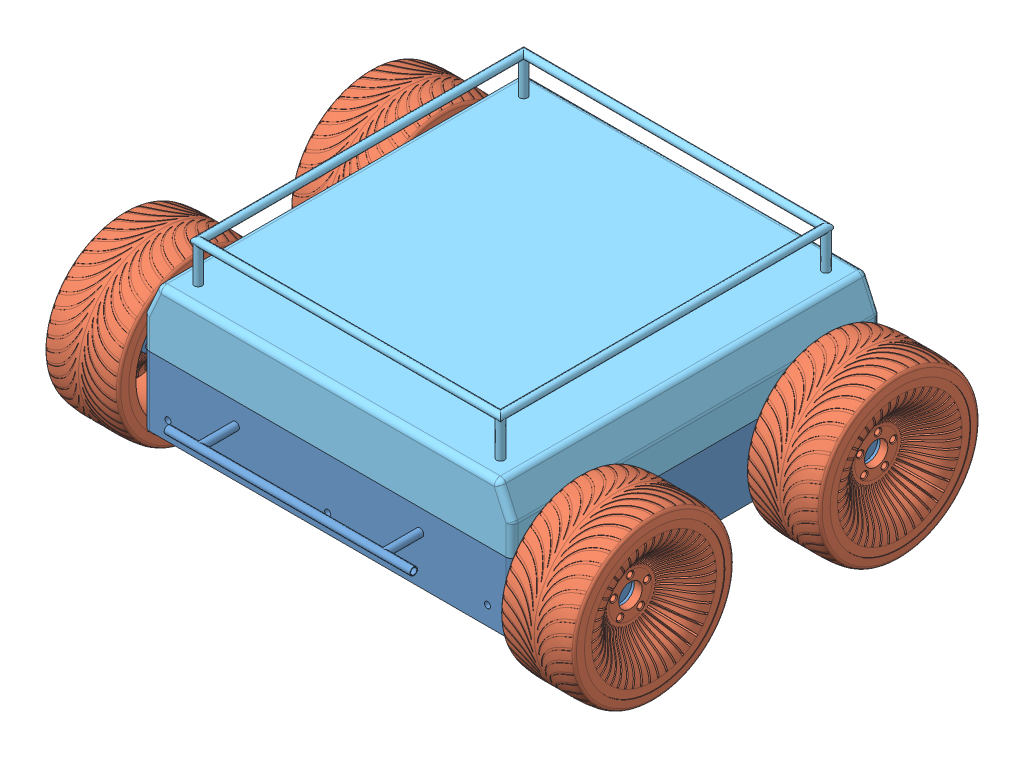
SolidWorks assembly FINAL UGV, configuration Default. Lengths in mm.
Overall size (1744.11 737.37 1465).
11 component instances, 5 part files, 28 mates.
Components (placement in the parent):
- BASE - Copy-2: BASE - Copy [Default<As Machined>] at (827.8363 661.6568 1059.2236) size (1520 225 1465)
- 18 x 9.5 wheel-3: 18 x 9.5 wheel [Default] at (1587.8363 756.6568 659.2236) x (1 0 0) z (0 0.112104 0.993697) size (252.9 542.37 542.37)
- 18 x 9.5 wheel-4: 18 x 9.5 wheel [Default] at (1587.8363 756.6568 1459.2236) size (252.9 542.37 542.37)
- 18 x 9.5 wheel-5: 18 x 9.5 wheel [Default] at (67.8363 756.6568 659.2236) x (-1 0 0) z (0 0 -1) size (252.9 542.37 542.37)
- 18 x 9.5 wheel-6: 18 x 9.5 wheel [Default] at (67.8363 756.6568 1459.2236) x (-1 0 0) z (0 0 -1) size (252.9 542.37 542.37)
- chassis-1: chassis [Default<As Machined>] at (1295.9851 766.5317 2607.767) size (1075 344.87 1105)
- Motenergy ME1114-1: Motenergy ME1114 [Default] at (405.8363 756.6568 659.2236) x (0 -1 -0.000674) z (-1 0 0) size (200 240 212.88)
- Motenergy ME1114-2: Motenergy ME1114 [Default] at (1229.8363 756.6568 1459.8036) x (0 -1 0) z (1 0 0) size (200 240 212.88)
- Motenergy ME1114-3: Motenergy ME1114 [Default] at (1229.8363 756.6568 658.6436) x (0 1 0) z (1 0 0) size (200 240 212.88)
- Motenergy ME1114-4: Motenergy ME1114 [Default] at (405.8363 756.6568 1459.8036) x (0 -1 0) z (-1 0 0) size (200 240 212.88)
- top-2: top [Default<As Machined>] at (827.8363 789.6568 459.2236) size (1200 332.5 1200)
Mates (geometry in assembly coordinates):
- Concentric3: concentric: circle of BASE - Copy-2; circle of 18 x 9.5 wheel-3
- Coincident5: coincident: plane of BASE - Copy-2 through (1587.8363 756.6568 659.2236) normal (1 0 0); plane of 18 x 9.5 wheel-3 through (1587.8363 832.8295 650.6302) normal (-1 0 0)
- Parallel3: parallel: cylinder of BASE - Copy-2 through (1577.8363 774.3187 713.5813) axis (1 0 0) radius 9.525; cylinder of 18 x 9.5 wheel-3 through (1448.9259 813.4466 652.8169) axis (1 0 0) radius 9.525
- Concentric5: concentric: circle of BASE - Copy-2; circle of 18 x 9.5 wheel-4
- Coincident6: coincident: plane of BASE - Copy-2 through (1587.8363 756.6568 1459.2236) normal (1 0 0); plane of 18 x 9.5 wheel-4 through (1587.8363 833.3127 1459.2236) normal (-1 0 0)
- Concentric6: concentric: circle of BASE - Copy-2; circle of 18 x 9.5 wheel-5
- Coincident7: coincident: plane of BASE - Copy-2 through (67.8363 756.6568 659.2236) normal (-1 0 0); plane of 18 x 9.5 wheel-5 through (67.8363 833.3127 659.2236) normal (1 0 0)
- Coincident9: coincident: cylinder of BASE - Copy-2 through (67.8363 774.3171 604.8707) axis (1 0 0) radius 9.525; circle of 18 x 9.5 wheel-5
- Coincident10: coincident: plane of BASE - Copy-2 through (67.8363 756.6568 1459.2236) normal (-1 0 0); plane of 18 x 9.5 wheel-6 through (67.8363 833.3127 1459.2236) normal (1 0 0)
- Concentric7: concentric: circle of BASE - Copy-2; circle of 18 x 9.5 wheel-6
- Distance5: distance = 0 mm: cylinder of Motenergy ME1114-1 through (386.2363 756.6568 659.2236) axis (-1 0 0) radius 11.115; cylinder of BASE - Copy-2 through (377.8363 756.6568 659.2236) axis (-1 0 0) radius 20
- Distance6: distance = 45 mm: plane of Motenergy ME1114-1 through (392.8363 756.6298 699.2236) normal (-1 0 0); plane of BASE - Copy-2 through (347.8363 756.6568 659.2236) normal (1 0 0)
- Distance8: distance = 45 mm: plane of BASE - Copy-2 through (247.8363 861.6568 479.2236) normal (1 0 0); line of chassis-1 through (292.8363 756.6568 1419.2236) axis (0 0 -1)
- Concentric10: concentric: circle of BASE - Copy-2; circle of chassis-1
- Coincident21: coincident: cylinder of BASE - Copy-2 through (1307.8363 756.6568 659.2236) axis (1 0 0) radius 40; circle of chassis-1
- Coincident24: coincident: plane of chassis-1 through (1295.9851 766.5317 1579.8036) normal (0 0 -1); plane of Motenergy ME1114-2 through (1229.8363 756.6568 1579.8036) normal (0 0 1)
- Coincident25: coincident: plane of chassis-1 through (1135.2363 801.6568 1579.8036) normal (-1 0 0); plane of Motenergy ME1114-2 through (1135.2363 801.6568 1339.8026) normal (-1 0 0)
- Coincident31: coincident: plane of chassis-1 through (1295.9851 766.5317 538.6436) normal (0 0 1); plane of Motenergy ME1114-3 through (1229.8363 756.6568 538.6436) normal (0 0 -1)
- Coincident32: coincident: plane of chassis-1 through (1135.2363 801.6568 538.6436) normal (0 1 0); plane of Motenergy ME1114-3 through (1190.2363 801.6568 778.6446) normal (0 1 0)
- Coincident33: coincident: plane of chassis-1 through (1135.2363 801.6568 538.6436) normal (-1 0 0); plane of Motenergy ME1114-3 through (1135.2363 711.6568 778.6446) normal (-1 0 0)
- Parallel11: parallel: plane of chassis-1 through (1295.9851 801.6568 2607.767) normal (0 1 0); plane of Motenergy ME1114-3 through (1190.2363 801.6568 558.4726) normal (0 1 0)
- Distance13: distance = 0 mm: plane of Motenergy ME1114-4 through (405.8363 756.6568 1579.8036) normal (0 0 1); plane of chassis-1 through (1295.9851 766.5317 1579.8036) normal (0 0 -1)
- Coincident36: coincident: plane of chassis-1 through (1295.9851 801.6568 2607.767) normal (0 1 0); plane of Motenergy ME1114-4 through (445.4363 801.6568 1579.8046) normal (0 1 0)
- Coincident37: coincident: plane of chassis-1 through (500.4363 711.6568 2607.767) normal (1 0 0); plane of Motenergy ME1114-4 through (500.4363 801.6568 1579.8046) normal (1 0 0)
- Coincident38: coincident: plane of BASE - Copy-2 through (1407.8363 861.6568 1639.2236) normal (0 1 0); plane of top-2 through (1427.8363 861.6568 1639.2236) normal (0 -1 0)
- Coincident39: coincident: plane of BASE - Copy-2 through (247.8363 861.6568 1659.2236) normal (0 0 1); plane of top-2 through (827.8363 789.6568 1659.2236) normal (0 0 1)
- Coincident40: coincident: plane of BASE - Copy-2 through (1427.8363 861.6568 479.2236) normal (1 0 0); plane of top-2 through (1427.8363 861.6568 1639.2236) normal (1 0 0)
- Coincident41: coincident: plane of chassis-1 through (1295.9851 801.6568 2607.767) normal (0 1 0); plane of Motenergy ME1114-2 through (1190.2363 801.6568 1559.9746) normal (0 1 0)
